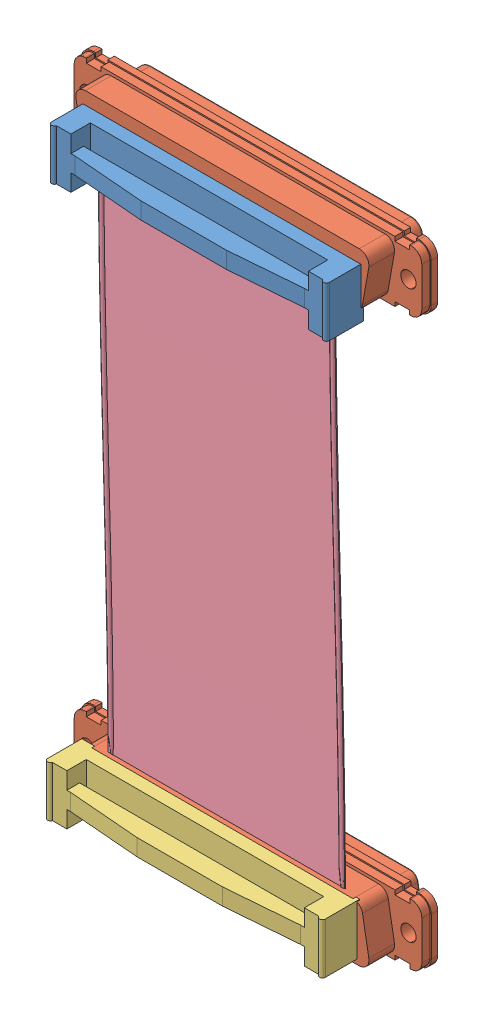
SolidWorks assembly Male to Male, configuration Default. Lengths in mm.
Overall size (69.32 124.59 19.32).
9 component instances, 4 part files, 0 mates.
Components (placement in the parent):
- Male to Male.stp-1: Male to Male.stp [Default] at origin size (69.32 124.59 19.32)
  - Ribbon Cable Male.stp-1: Ribbon Cable Male.stp [Default] at (490.9319 614.6973 61.2515) size (69.32 13.33 19.3)
    - Ribbon mount.stp-1: Ribbon mount.stp [Default] at (-23.2505 -30.4698 -3.4931) x (1 0 0) z (0 0 -1) size (55 10 8.13)
    - DBConnector.stp-1: DBConnector.stp [Default] at (-23.1548 -28.4181 -17.0567) x (-1 0 0) z (0 0 -1) size (69.32 12.55 11.76)
  - Ribbon Cable Male Both Directions.stp-1: Ribbon Cable Male Both Directions.stp [Default] at (484.189 487.9145 42.8847) x (-1 0 0) z (0 0 1) size (69.32 12.55 19.3)
    - DBConnector.stp-1: DBConnector.stp [Default] at (16.4119 13.6749 1.2952) x (-1 0 0) z (0 0 -1) size (69.32 12.55 11.76)
    - 180138 Both Directions.stp-1: 180138 Both Directions.stp [Default] at (17.3162 13.2266 14.8588) x (-1 0 0) z (0 0 -1) size (55 10 8.13)
  - Male to Male.Harness2.stp-1: Male to Male.Harness2.stp [Default] at origin size (48.94 108.8 2.31)
    - Male to Male.Harness2_1.stp-1: Male to Male.Harness2_1.stp [Default] at origin size (48.94 108.8 2.31)
